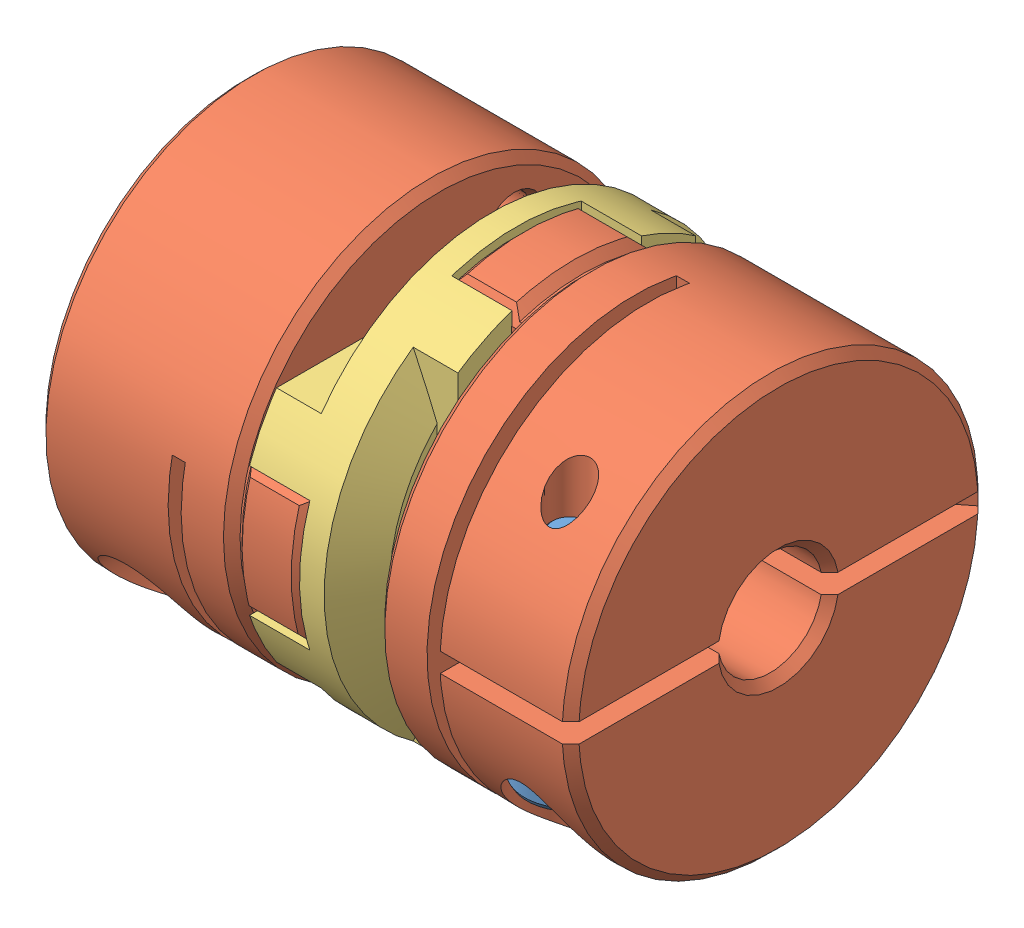
SolidWorks assembly GE-19243, configuration Default. Lengths in mm.
Overall size (32.56 25.4 25.4).
7 component instances, 3 part files, 6 mates.
Components (placement in the parent):
- GE-19242-1: GE-19242 [Default] at (-9.5537 30.5082 17.0985) size (16 25.4 25.4)
  - Ruland_metric socket head cap screws 1_cfm3_10-1: Ruland_metric socket head cap screws 1_cfm3_10 [Default] at (8.255 -22.7076 6.731) size (5.5 5.5 13)
  - Ruland_oct-moct_oct16-4-a-d-1: Ruland_oct-moct_oct16-4-a-d [Default] at (4.2672 -13.9446 3.7211) size (16 25.4 25.4)
- GE-19242-2: GE-19242 [Default] at (31.5435 20.2847 6.875) x (-1 0 0) z (0 -1 0) size (16 25.4 25.4)
  - Ruland_metric socket head cap screws 1_cfm3_10-1: Ruland_metric socket head cap screws 1_cfm3_10 [Default] at (8.255 -22.7076 6.731) size (5.5 5.5 13)
  - Ruland_oct-moct_oct16-4-a-d-1: Ruland_oct-moct_oct16-4-a-d [Default] at (4.2672 -13.9446 3.7211) size (16 25.4 25.4)
- GE-19241-1: GE-19241 [Default] at (14.9573 16.5636 20.8196) x (0 1 0) z (-1 0 0) size (25.4 25.4 7.92)
Mates (geometry in assembly coordinates):
- Concentric1: concentric: circle of GE-19242-1/Ruland_oct-moct_oct16-4-a-d-1; circle of GE-19241-1
- Parallel1: parallel: plane of GE-19242-1/Ruland_oct-moct_oct16-4-a-d-1 through (6.5753 12.5821 20.8196) normal (0 -1 0); plane of GE-19241-1 through (10.7155 12.6075 8.7515) normal (0 1 0)
- Coincident2: coincident: plane of GE-19242-1/Ruland_oct-moct_oct16-4-a-d-1 through (10.7155 19.7386 20.8196) normal (1 0 0); plane of GE-19241-1 through (10.7155 16.5636 20.8196) normal (-1 0 0)
- Concentric2: concentric: circle of GE-19242-2/Ruland_oct-moct_oct16-4-a-d-1; circle of GE-19241-1
- Parallel2: parallel: plane of GE-19242-2/Ruland_oct-moct_oct16-4-a-d-1 through (15.4145 16.5636 24.8011) normal (0 0 1); plane of GE-19241-1 through (11.2743 28.6317 24.7757) normal (0 0 -1)
- Coincident4: coincident: plane of GE-19242-2/Ruland_oct-moct_oct16-4-a-d-1 through (11.2743 16.5636 17.6446) normal (-1 0 0); plane of GE-19241-1 through (11.2743 16.5636 20.8196) normal (1 0 0)
